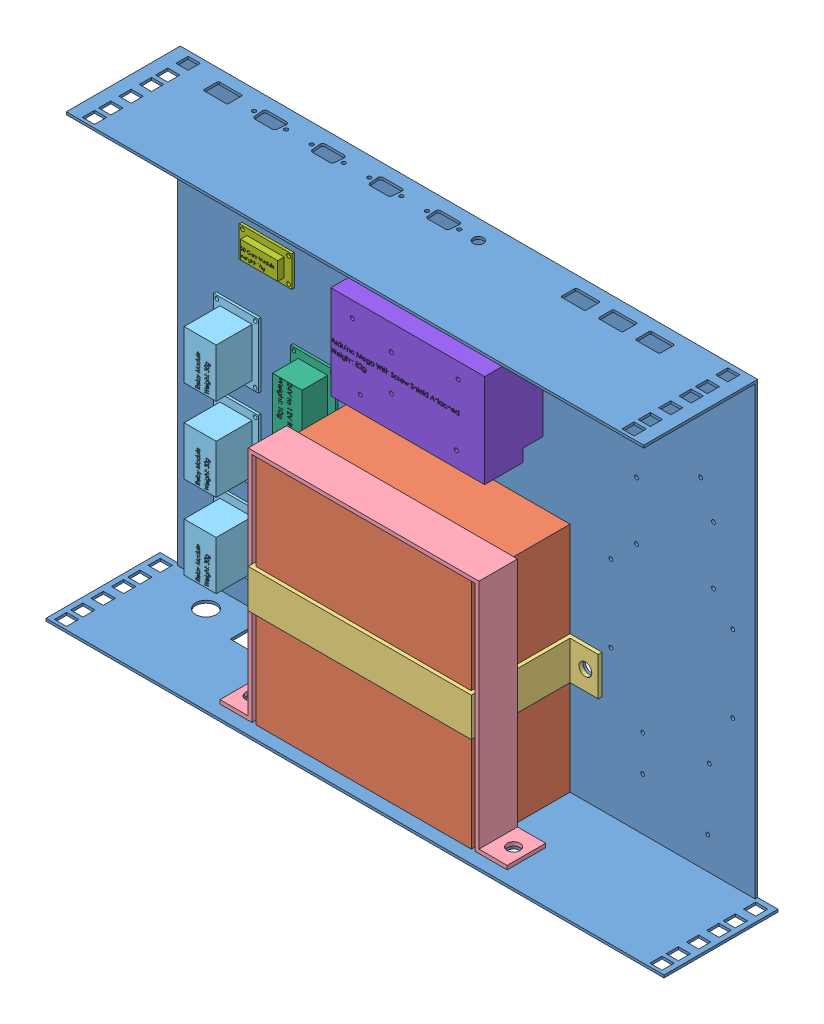
SolidWorks assembly Tray with All components, configuration Default. Lengths in mm.
Overall size (482 352 88.9).
10 component instances, 8 part files, 27 mates.
Components (placement in the parent):
- Tray fix-1: Tray fix [Default] at (-140.6124 -26.842 47.9853) size (482 352 88.9)
- Battery-1: Battery [Default] at (-227.8124 -19.842 49.9853) size (168 181 77)
- Battery strap 77mm high-1: Battery strap 77mm high [Default] at (-143.8124 -123.842 49.9853) x (-1 0 0) z (0 1 0) size (218 80 30)
- Battery strap 181mm long-1: Battery strap 181mm long [Default] at (-143.8124 -200.842 96.9853) size (224 184 30)
- Relay Module V3-1: Relay Module V3 [Default] at (-318.3124 -155.842 49.9853) x (-1 0 0) z (0 1 0) size (35 30 50)
- Relay Module V3-2: Relay Module V3 [Default] at (-318.3124 -90.842 49.9853) x (-1 0 0) z (0 1 0) size (35 30 50)
- Relay Module V3-3: Relay Module V3 [Default] at (-318.3124 -25.842 49.9853) x (-1 0 0) z (0 1 0) size (35 30 50)
- 24 to 12V regulator-1: 24 to 12V regulator [Default] at (-258.3124 -38.342 49.9853) size (35 65 22)
- SD Card module-1: SD Card module [Default] at (-295.3124 44.158 49.9853) size (41 24 7)
- Arduino Mega with Screw Shield Attached-1: Arduino Mega with Screw Shield Attached [Default] at (-140.8124 55.658 49.9853) size (120 73 45.59)
Mates (geometry in assembly coordinates):
- Coincident1: coincident anti-aligned: plane of Tray fix-1 through (-140.6124 -26.842 49.9853) normal (0 0 1); plane of Battery-1 through (-227.8124 -19.842 49.9853) normal (0 0 -1)
- Coincident2: coincident anti-aligned: plane of Tray fix-1 through (-140.6124 -200.842 47.9853) normal (0 1 0); plane of Battery-1 through (-227.8124 -200.842 126.9853) normal (0 -1 0)
- Distance1: distance = 138 mm: line of Tray fix-1 through (-365.8124 147.158 49.9853) axis (0 -1 0); plane of Battery-1 through (-227.8124 -19.842 126.9853) normal (-1 0 0)
- Coincident6: coincident anti-aligned: plane of Battery-1 through (-227.8124 -19.842 126.9853) normal (0 0 1); plane of Battery strap 77mm high-1 through (-59.8124 -93.842 126.9853) normal (0 0 -1)
- Coincident7: coincident anti-aligned: plane of Battery-1 through (-227.8124 -19.842 126.9853) normal (-1 0 0); plane of Battery strap 77mm high-1 through (-227.8124 -93.842 126.9853) normal (1 0 0)
- Distance3: distance = 77 mm anti-aligned: plane of Battery strap 77mm high-1 through (-143.8124 -123.842 49.9853) normal (0 -1 0); plane of Tray fix-1 through (-140.6124 -200.842 47.9853) normal (0 1 0)
- Coincident15: coincident anti-aligned: plane of Tray fix-1 through (-140.6124 -200.842 47.9853) normal (0 1 0); plane of Battery strap 181mm long-1 through (-255.8124 -200.842 126.9853) normal (0 -1 0)
- Concentric4: concentric anti-aligned: cylinder of Tray fix-1 through (-245.8124 149.159 111.9853) axis (0 -1 0) radius 5; cylinder of Battery strap 181mm long-1 through (-245.8124 -227.842 111.9853) axis (0 1 0) radius 5
- Concentric5: concentric anti-aligned: cylinder of Tray fix-1 through (-41.8124 149.159 111.9853) axis (0 -1 0) radius 5; circle of Battery strap 181mm long-1
- Coincident20: coincident: plane of Tray fix-1 through (-140.6124 -26.842 49.9853) normal (0 0 1); plane of Relay Module V3-1 through (-318.3124 -155.842 49.9853) normal (0 0 -1)
- Concentric10: concentric: cylinder of Tray fix-1 through (-333.3124 -133.342 19.9853) axis (0 0 1) radius 1.5; cylinder of Relay Module V3-1 through (-333.3124 -133.342 51.9853) axis (0 0 -1) radius 1.5
- Concentric11: concentric anti-aligned: cylinder of Tray fix-1 through (-303.3124 -178.342 19.9853) axis (0 0 1) radius 1.5; cylinder of Relay Module V3-1 through (-303.3124 -178.342 51.9853) axis (0 0 -1) radius 1.5
- Coincident21: coincident: plane of Tray fix-1 through (-140.6124 -26.842 49.9853) normal (0 0 1); plane of Relay Module V3-2 through (-318.3124 -90.842 49.9853) normal (0 0 -1)
- Coincident22: coincident: plane of Tray fix-1 through (-140.6124 -26.842 49.9853) normal (0 0 1); plane of Relay Module V3-3 through (-318.3124 -25.842 49.9853) normal (0 0 -1)
- Concentric12: concentric: cylinder of Tray fix-1 through (-333.3124 -113.342 19.9853) axis (0 0 1) radius 1.5; cylinder of Relay Module V3-2 through (-333.3124 -113.342 51.9853) axis (0 0 -1) radius 1.5
- Concentric13: concentric: cylinder of Tray fix-1 through (-333.3124 -48.342 19.9853) axis (0 0 1) radius 1.5; cylinder of Relay Module V3-3 through (-333.3124 -48.342 51.9853) axis (0 0 -1) radius 1.5
- Concentric14: concentric anti-aligned: cylinder of Tray fix-1 through (-303.3124 -68.342 19.9853) axis (0 0 1) radius 1.5; cylinder of Relay Module V3-2 through (-303.3124 -68.342 51.9853) axis (0 0 -1) radius 1.5
- Concentric15: concentric anti-aligned: cylinder of Tray fix-1 through (-303.3124 -3.342 19.9853) axis (0 0 1) radius 1.5; cylinder of Relay Module V3-3 through (-303.3124 -3.342 51.9853) axis (0 0 -1) radius 1.5
- Coincident23: coincident: plane of Tray fix-1 through (-140.6124 -26.842 49.9853) normal (0 0 1); plane of 24 to 12V regulator-1 through (-258.3124 -38.342 49.9853) normal (0 0 -1)
- Concentric16: concentric: cylinder of Tray fix-1 through (-243.3124 -68.342 19.9853) axis (0 0 1) radius 1.5; cylinder of 24 to 12V regulator-1 through (-243.3124 -68.342 51.9853) axis (0 0 -1) radius 1.5
- Concentric17: concentric anti-aligned: cylinder of Tray fix-1 through (-273.3124 -8.342 19.9853) axis (0 0 1) radius 1.5; cylinder of 24 to 12V regulator-1 through (-273.3124 -8.342 51.9853) axis (0 0 -1) radius 1.5
- Coincident24: coincident: plane of Tray fix-1 through (-140.6124 -26.842 49.9853) normal (0 0 1); plane of SD Card module-1 through (-295.3124 44.158 49.9853) normal (0 0 -1)
- Coincident25: coincident: circle of Tray fix-1; cylinder of SD Card module-1 through (-313.3124 34.658 51.9853) axis (0 0 -1) radius 1.5
- Concentric18: concentric anti-aligned: cylinder of Tray fix-1 through (-277.3124 53.658 47.9843) axis (0 0 1) radius 1.5; cylinder of SD Card module-1 through (-277.3124 53.658 51.9853) axis (0 0 -1) radius 1.5
- Concentric19: concentric: cylinder of Tray fix-1 through (-184.0104 79.919 47.9843) axis (0 0 1) radius 1.5; cylinder of Arduino Mega with Screw Shield Attached-1 through (-184.0104 79.919 65.5753) axis (0 0 -1) radius 1.5
- Concentric20: concentric: cylinder of Tray fix-1 through (-153.5624 72.302 47.9843) axis (0 0 1) radius 1.5; cylinder of Arduino Mega with Screw Shield Attached-1 through (-153.5624 72.302 65.5753) axis (0 0 -1) radius 1.5
- Coincident26: coincident anti-aligned: plane of Tray fix-1 through (-140.6124 -26.842 49.9853) normal (0 0 1); plane of Arduino Mega with Screw Shield Attached-1 through (-140.8124 55.658 49.9853) normal (0 0 -1)
